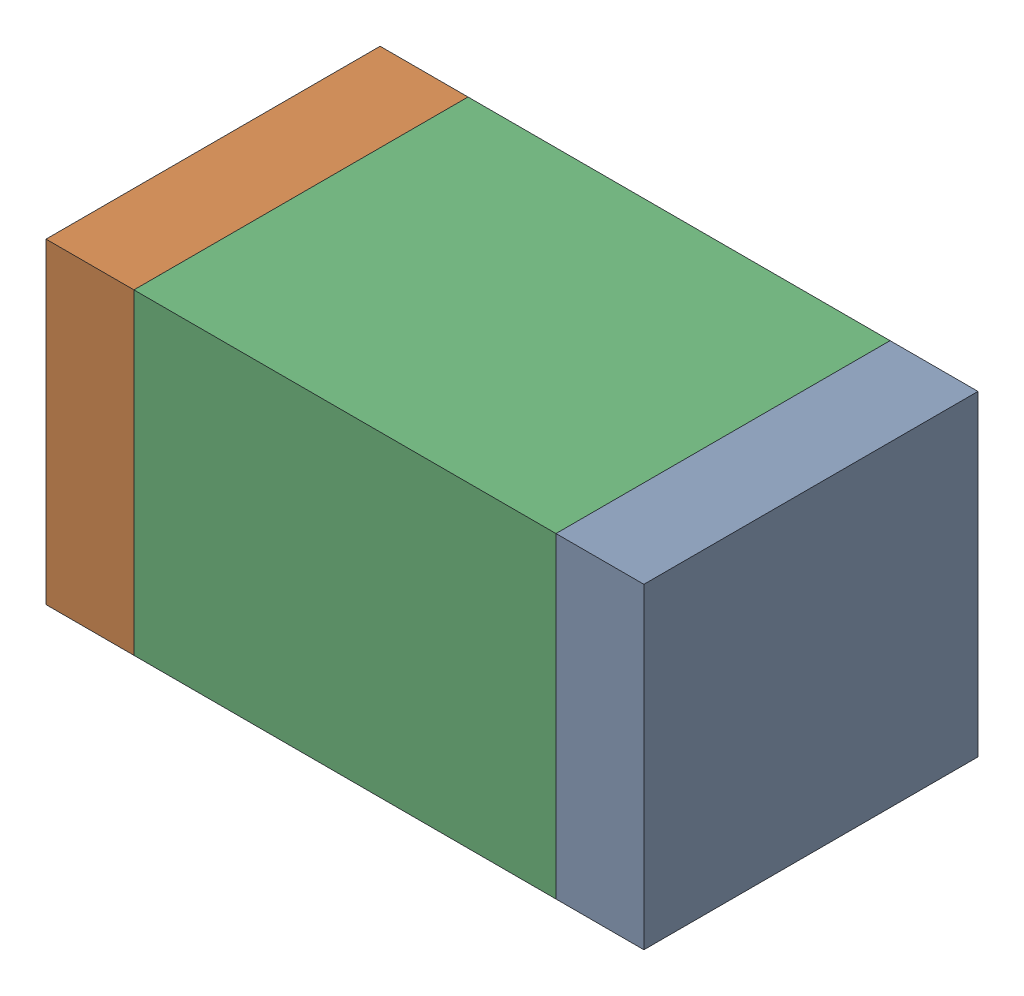
SolidWorks assembly C1-1, configuration Default. Lengths in mm.
Overall size (3.4 1.8 1.9).
6 component instances, 2 part files, 0 mates.
Components (placement in the parent):
- 959208392-1-1: 959208392-1 [Default] at (133.022 83.687 0) size (0.5 1.8 1.9)
  - Extruded-43-1: Extruded-43 [Default] at origin size (0.5 1.8 1.9)
- 959208392-1-2: 959208392-1 [Default] at (130.122 83.687 0) size (0.5 1.8 1.9)
  - Extruded-43-1: Extruded-43 [Default] at origin size (0.5 1.8 1.9)
- 959208256-1-1: 959208256-1 [Default] at (131.572 83.687 0) size (2.4 1.8 1.9)
  - Extruded-44-1: Extruded-44 [Default] at origin size (2.4 1.8 1.9)
